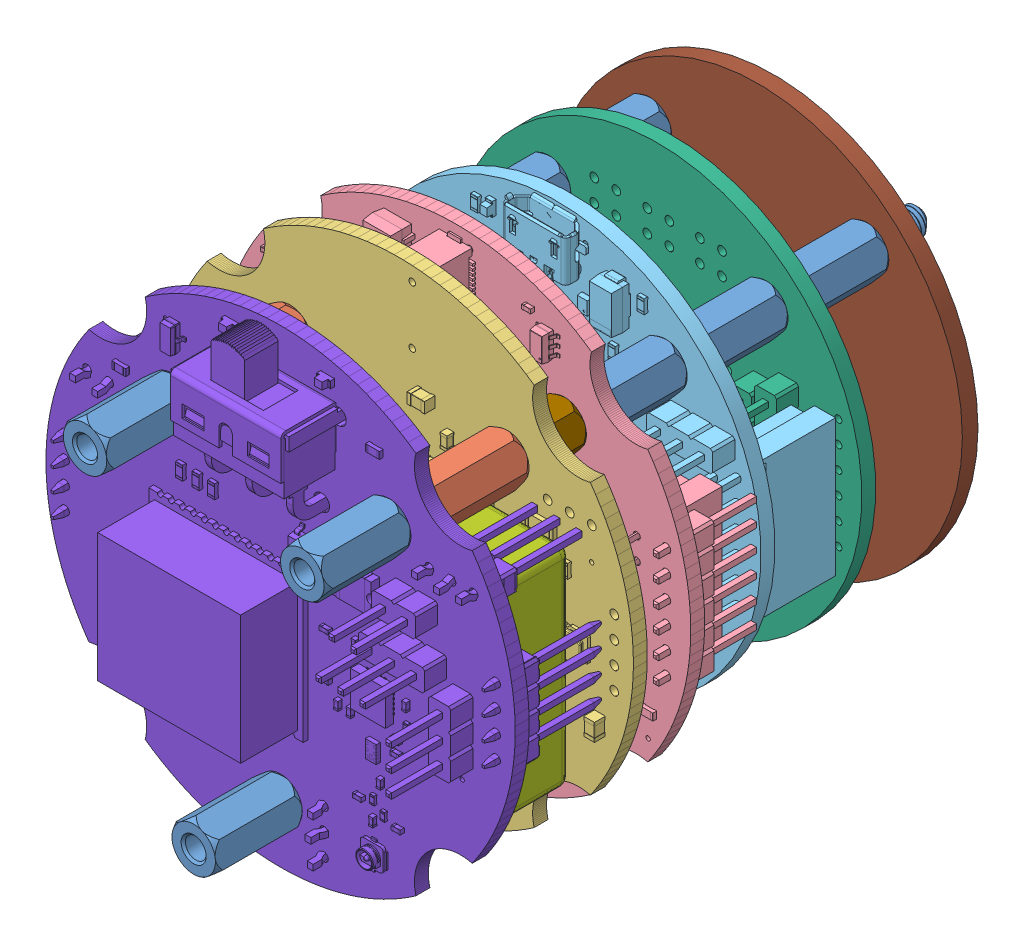
SolidWorks assembly asmPCBs, configuration Default. Lengths in mm.
Overall size (115.92 54.48 71.46).
30 component instances, 13 part files, 60 mates.
Components (placement in the parent):
- Hex Spacer MF M3 L10mm-25: Hex Spacer MF M3 L10mm [Default] at (-77.0093 15.9239 22.7752) x (0.987208 0.159439 0) z (0 0 -1) size (6.67 6.55 16.46)
- Hex Spacer MF M3 L10mm-24: Hex Spacer MF M3 L10mm [Default] at (-49.4701 6.9795 22.7752) x (0.923728 0.383049 0) z (0 0 -1) size (6.67 6.55 16.46)
- Hex Spacer MF M3 L12mm-26: Hex Spacer MF M3 L12mm [Default] at (31.272 -32.1614 9.1752) x (-0.938217 0.346047 0) z (0 0 -1) size (7.82 9.65 20.19)
- Hex Spacer MF M3 L12mm-27: Hex Spacer MF M3 L12mm [Default] at (-13.4807 82.2938 9.1752) x (0.015996 -0.999872 0) z (0 0 -1) size (7.82 9.65 20.19)
- Hex Spacer MF M3 L12mm-28: Hex Spacer MF M3 L12mm [Default] at (-10.1897 -31.112 9.1752) x (-0.455522 0.890225 0) z (0 0 -1) size (7.82 9.65 20.19)
- PCB_B-1: PCB_B [Default] at (-25.021 8.8014 7.5752) size (53.99 53.99 3.2)
- PCB_C-1: PCB_C [Default] at (-25.021 8.8014 0.9752) size (53.99 54.16 14.64)
- Hex Spacer MF M3 L10mm-26: Hex Spacer MF M3 L10mm [Default] at (-64.6583 -16.7727 22.7752) x (0.990934 0.134353 0) z (0 0 -1) size (6.67 6.55 16.46)
- PCB_D-1: PCB_D [Default] at (-25.021 8.8014 -10.6248) size (47 47 18.65)
- Hex Spacer MF M3 L10mm-28: Hex Spacer MF M3 L10mm [Default] at (-0.5719 37.6234 -9.0248) x (-0.923728 -0.383049 0) z (0 0 -1) size (6.67 6.55 16.46)
- Hex Spacer MF M3 L10mm-29: Hex Spacer MF M3 L10mm [Default] at (24.4281 37.6234 -9.0248) x (-0.923728 -0.383049 0) z (0 0 -1) size (6.67 6.55 16.46)
- Hex Spacer MF M3 L10mm-30: Hex Spacer MF M3 L10mm [Default] at (11.9281 3.9234 -9.0248) x (-0.923728 -0.383049 0) z (0 0 -1) size (6.67 6.55 16.46)
- Hex Spacer MF M3 L10mm-18: Hex Spacer MF M3 L10mm [Default] at (0.6106 34.3837 -20.6248) x (-0.95329 -0.302056 0) z (0 0 -1) size (6.67 6.55 16.46)
- Hex Spacer MF M3 L10mm-16: Hex Spacer MF M3 L10mm [Default] at (11.8127 4.1987 -20.6248) x (-0.920844 -0.389932 0) z (0 0 -1) size (6.67 6.55 16.46)
- Hex Spacer MF M3 L10mm-17: Hex Spacer MF M3 L10mm [Default] at (24.4281 37.6234 -20.6248) x (-0.923728 -0.383049 0) z (0 0 -1) size (6.67 6.55 16.46)
- PCB_E-1: PCB_E [Default] at (-25.021 8.8014 -22.2248) size (47 47 11.54)
- Bateria Li-Po-1: Bateria Li-Po [Default] at (-24.6522 6.5974 19.2752) x (1 0 0) z (0 1 0) size (42 8.5 24)
- PCB_A-3: PCB_A [Default] at (-25.021 8.8014 21.1752) size (53.99 54.31 20.71)
- Hex Spacer MF M3 L5mm-1: Hex Spacer MF M3 L5mm [Default] at (-34.2583 -15.229 2.5752) x (-0.923728 -0.383049 0) z (0 0 -1) size (7.82 9.65 13.19)
- Hex Spacer MF M3 L5mm-2: Hex Spacer MF M3 L5mm [Default] at (-21.7583 18.471 2.5752) x (-0.923728 -0.383049 0) z (0 0 -1) size (7.82 9.65 13.19)
- Hex Spacer MF M3 L5mm-3: Hex Spacer MF M3 L5mm [Default] at (-27.7771 24.5501 2.5752) x (0.97439 0.224864 0) z (0 0 -1) size (7.82 9.65 13.19)
- ESP32-WROOM-1: ESP32-WROOM [Default] at (-23.921 8.3714 2.5402) size (18.07 25.54 3.04)
- Hex Spacer MF M3 L10mm-31: Hex Spacer MF M3 L10mm [Default] at (14.9788 -11.5195 -32.2248) x (-0.999995 0.003024 0) z (0 0 -1) size (6.67 6.55 16.46)
- Hex Spacer MF M3 L10mm-32: Hex Spacer MF M3 L10mm [Default] at (24.4281 37.6234 -32.2248) x (-0.923728 -0.383049 0) z (0 0 -1) size (6.67 6.55 16.46)
- Hex Spacer MF M3 L10mm-33: Hex Spacer MF M3 L10mm [Default] at (-0.5719 37.6234 -32.2248) x (-0.923728 -0.383049 0) z (0 0 -1) size (6.67 6.55 16.46)
- Soporte-antena-1: Soporte-antena [Predeterminado] at (-25.0593 8.8938 -32.2248) x (-1 0 0) z (0 0 -1) size (47 47 1.8)
- Antena-1: Antena [Default] at (-20.5593 2.8938 -33.8248) x (-1 0 0) z (0 0 -1) size (19 14 2.55)
  - 0915AT43A0026E-1: 0915AT43A0026E [Default] at (2.7432 4.6736 1.65) size (8 2 0.9)
    - COMPOUND-1: COMPOUND [Default] at origin size (8 2 0.9)
  - COMPOUND_2-1: COMPOUND_2 [Default] at origin size (19 14 1.6)
Mates (geometry in assembly coordinates):
- Coincident40: coincident anti-aligned: plane of Hex Spacer MF M3 L10mm-24 through (-15.8533 23.6802 22.7752) normal (0 0 -1); plane of PCB_A-3 through (-4.9206 24.2485 22.7752) normal (0 0 1)
- Coincident42: coincident anti-aligned: plane of Hex Spacer MF M3 L10mm-26 through (-27.8905 -9.2143 22.7752) normal (0 0 -1); plane of PCB_A-3 through (-4.9206 24.2485 22.7752) normal (0 0 1)
- Coincident43: coincident anti-aligned: plane of Hex Spacer MF M3 L12mm-27 through (-10.0121 24.8919 9.1752) normal (0 0 -1); plane of PCB_B-1 through (-4.9206 24.2485 9.1752) normal (0 0 1)
- Concentric38: concentric aligned: cylinder of Hex Spacer MF M3 L10mm-24 through (-12.521 22.3014 26.5318) axis (0 0 1) radius 1.2; cylinder of PCB_A-3 through (-12.521 22.3014 20.3752) axis (0 0 1) radius 1.6
- Concentric39: concentric aligned: cylinder of Hex Spacer MF M3 L10mm-26 through (-25.021 -11.3986 26.5318) axis (0 0 1) radius 1.2; cylinder of PCB_A-3 through (-25.021 -11.3986 20.3752) axis (0 0 1) radius 1.6
- Concentric40: concentric aligned: cylinder of Hex Spacer MF M3 L10mm-24 through (-12.521 22.3014 26.5318) axis (0 0 1) radius 1.2; cylinder of Hex Spacer MF M3 L12mm-27 through (-12.521 22.3014 14.9318) axis (0 0 1) radius 1.2
- Concentric45: concentric aligned: cylinder of Hex Spacer MF M3 L10mm-25 through (-37.521 22.3014 26.5318) axis (0 0 1) radius 1.2; cylinder of PCB_A-3 through (-37.521 22.3014 20.3752) axis (0 0 1) radius 1.6
- Coincident49: coincident anti-aligned: plane of Hex Spacer MF M3 L10mm-25 through (-40.4449 24.4123 22.7752) normal (0 0 -1); plane of PCB_A-3 through (-4.9206 24.2485 22.7752) normal (0 0 1)
- Concentric46: concentric aligned: cylinder of Hex Spacer MF M3 L10mm-25 through (-37.521 22.3014 26.5318) axis (0 0 1) radius 1.2; cylinder of Hex Spacer MF M3 L12mm-28 through (-37.521 22.3014 14.9318) axis (0 0 1) radius 1.2
- Coincident50: coincident anti-aligned: plane of Hex Spacer MF M3 L12mm-28 through (-38.6295 18.8698 21.1752) normal (0 0 1); plane of PCB_A-3 through (-4.9206 24.2485 21.1752) normal (0 0 -1)
- Concentric47: concentric aligned: cylinder of Hex Spacer MF M3 L10mm-24 through (-12.521 22.3014 26.5318) axis (0 0 1) radius 1.2; cylinder of Hex Spacer MF M3 L12mm-27 through (-12.521 22.3014 14.9318) axis (0 0 1) radius 1.2
- Coincident51: coincident anti-aligned: plane of Hex Spacer MF M3 L12mm-27 through (-10.0121 24.8919 21.1752) normal (0 0 1); plane of PCB_A-3 through (-4.9206 24.2485 21.1752) normal (0 0 -1)
- Concentric49: concentric aligned: cylinder of Hex Spacer MF M3 L12mm-26 through (-25.021 -11.3986 14.9318) axis (0 0 1) radius 1.2; cylinder of Hex Spacer MF M3 L10mm-26 through (-25.021 -11.3986 26.5318) axis (0 0 1) radius 1.2
- Coincident52: coincident anti-aligned: plane of Hex Spacer MF M3 L12mm-26 through (-23.511 -14.6734 21.1752) normal (0 0 1); plane of PCB_A-3 through (-4.9206 24.2485 21.1752) normal (0 0 -1)
- Concentric50: concentric aligned: cylinder of Hex Spacer MF M3 L10mm-25 through (-37.521 22.3014 26.5318) axis (0 0 1) radius 1.2; cylinder of PCB_B-1 through (-37.521 22.3014 6.7752) axis (0 0 1) radius 1.6
- Concentric51: concentric aligned: cylinder of Hex Spacer MF M3 L10mm-24 through (-12.521 22.3014 26.5318) axis (0 0 1) radius 1.2; cylinder of PCB_B-1 through (-12.521 22.3014 6.7752) axis (0 0 1) radius 1.6
- Concentric52: concentric aligned: cylinder of Hex Spacer MF M3 L5mm-1 through (-25.021 -11.3986 5.3318) axis (0 0 1) radius 1.2; cylinder of PCB_C-1 through (-25.021 -11.3986 0.1752) axis (0 0 1) radius 1.6
- Concentric53: concentric aligned: cylinder of Hex Spacer MF M3 L5mm-2 through (-12.521 22.3014 5.3318) axis (0 0 1) radius 1.2; cylinder of PCB_C-1 through (-12.521 22.3014 0.1752) axis (0 0 1) radius 1.6
- Concentric54: concentric aligned: cylinder of Hex Spacer MF M3 L5mm-3 through (-37.521 22.3014 5.3318) axis (0 0 1) radius 1.2; cylinder of PCB_C-1 through (-37.521 22.3014 0.1752) axis (0 0 1) radius 1.6
- Coincident54: coincident anti-aligned: plane of PCB_C-1 through (-4.9206 24.2485 2.5752) normal (0 0 1); plane of Hex Spacer MF M3 L5mm-2 through (-9.1887 20.9227 2.5752) normal (0 0 -1)
- Coincident55: coincident anti-aligned: plane of PCB_C-1 through (-4.9206 24.2485 2.5752) normal (0 0 1); plane of Hex Spacer MF M3 L5mm-1 through (-21.6887 -12.7773 2.5752) normal (0 0 -1)
- Concentric55: concentric aligned: cylinder of Hex Spacer MF M3 L10mm-24 through (-12.521 22.3014 26.5318) axis (0 0 1) radius 1.2; cylinder of Hex Spacer MF M3 L5mm-2 through (-12.521 22.3014 5.3318) axis (0 0 1) radius 1.2
- Concentric56: concentric aligned: cylinder of Hex Spacer MF M3 L10mm-25 through (-37.521 22.3014 26.5318) axis (0 0 1) radius 1.2; cylinder of Hex Spacer MF M3 L5mm-3 through (-37.521 22.3014 5.3318) axis (0 0 1) radius 1.2
- Coincident56: coincident anti-aligned: plane of PCB_B-1 through (-4.9206 24.2485 7.5752) normal (0 0 -1); plane of Hex Spacer MF M3 L5mm-3 through (-40.5791 24.2127 7.5752) normal (0 0 1)
- Concentric57: concentric aligned: cylinder of Hex Spacer MF M3 L10mm-24 through (-12.521 22.3014 26.5318) axis (0 0 1) radius 1.2; cylinder of Hex Spacer MF M3 L10mm-29 through (-12.521 22.3014 -5.2682) axis (0 0 1) radius 1.2
- Concentric58: concentric aligned: cylinder of Hex Spacer MF M3 L10mm-25 through (-37.521 22.3014 26.5318) axis (0 0 1) radius 1.2; cylinder of Hex Spacer MF M3 L10mm-28 through (-37.521 22.3014 -5.2682) axis (0 0 1) radius 1.2
- Concentric59: concentric aligned: cylinder of Hex Spacer MF M3 L10mm-26 through (-25.021 -11.3986 26.5318) axis (0 0 1) radius 1.2; cylinder of Hex Spacer MF M3 L10mm-30 through (-25.021 -11.3986 -5.2682) axis (0 0 1) radius 1.2
- Coincident57: coincident anti-aligned: plane of PCB_C-1 through (-4.9206 24.2485 0.9752) normal (0 0 -1); plane of Hex Spacer MF M3 L10mm-28 through (-34.1887 20.9227 0.9752) normal (0 0 1)
- Coincident58: coincident anti-aligned: plane of PCB_C-1 through (-4.9206 24.2485 0.9752) normal (0 0 -1); plane of Hex Spacer MF M3 L10mm-29 through (-9.1887 20.9227 0.9752) normal (0 0 1)
- Coincident59: coincident anti-aligned: plane of PCB_C-1 through (-4.9206 24.2485 0.9752) normal (0 0 -1); plane of Hex Spacer MF M3 L10mm-30 through (-21.6887 -12.7773 0.9752) normal (0 0 1)
- Coincident60: coincident anti-aligned: plane of PCB_D-1 through (-1.521 8.8014 -9.0248) normal (0 0 1); plane of Hex Spacer MF M3 L10mm-28 through (-34.1887 20.9227 -9.0248) normal (0 0 -1)
- Concentric60: concentric aligned: cylinder of Hex Spacer MF M3 L10mm-25 through (-37.521 22.3014 26.5318) axis (0 0 1) radius 1.2; cylinder of PCB_D-1 through (-37.521 22.3014 -11.4248) axis (0 0 1) radius 1.6
- Concentric61: concentric aligned: cylinder of Hex Spacer MF M3 L10mm-24 through (-12.521 22.3014 26.5318) axis (0 0 1) radius 1.2; cylinder of PCB_D-1 through (-12.521 22.3014 -11.4248) axis (0 0 1) radius 1.6
- Concentric62: concentric aligned: cylinder of Hex Spacer MF M3 L10mm-25 through (-37.521 22.3014 26.5318) axis (0 0 1) radius 1.2; cylinder of Hex Spacer MF M3 L10mm-18 through (-37.521 22.3014 -16.8682) axis (0 0 1) radius 1.2
- Concentric63: concentric aligned: cylinder of Hex Spacer MF M3 L10mm-24 through (-12.521 22.3014 26.5318) axis (0 0 1) radius 1.2; cylinder of Hex Spacer MF M3 L10mm-17 through (-12.521 22.3014 -16.8682) axis (0 0 1) radius 1.2
- Concentric64: concentric aligned: cylinder of Hex Spacer MF M3 L10mm-26 through (-25.021 -11.3986 26.5318) axis (0 0 1) radius 1.2; cylinder of Hex Spacer MF M3 L10mm-16 through (-25.021 -11.3986 -16.8682) axis (0 0 1) radius 1.2
- Coincident61: coincident anti-aligned: plane of PCB_D-1 through (-1.521 8.8014 -10.6248) normal (0 0 -1); plane of Hex Spacer MF M3 L10mm-16 through (-21.6785 -12.7524 -10.6248) normal (0 0 1)
- Coincident62: coincident anti-aligned: plane of PCB_D-1 through (-1.521 8.8014 -10.6248) normal (0 0 -1); plane of Hex Spacer MF M3 L10mm-17 through (-9.1887 20.9227 -10.6248) normal (0 0 1)
- Coincident63: coincident anti-aligned: plane of PCB_D-1 through (-1.521 8.8014 -10.6248) normal (0 0 -1); plane of Hex Spacer MF M3 L10mm-18 through (-34.3199 20.6408 -10.6248) normal (0 0 1)
- Concentric65: concentric aligned: cylinder of Hex Spacer MF M3 L10mm-24 through (-12.521 22.3014 26.5318) axis (0 0 1) radius 1.2; cylinder of PCB_E-1 through (-12.521 22.3014 -23.0248) axis (0 0 1) radius 1.6
- Concentric66: concentric aligned: cylinder of Hex Spacer MF M3 L10mm-25 through (-37.521 22.3014 26.5318) axis (0 0 1) radius 1.2; cylinder of PCB_E-1 through (-37.521 22.3014 -23.0248) axis (0 0 1) radius 1.6
- Coincident64: coincident anti-aligned: plane of Hex Spacer MF M3 L10mm-17 through (-9.1887 20.9227 -20.6248) normal (0 0 -1); plane of PCB_E-1 through (-1.521 8.8014 -20.6248) normal (0 0 1)
- Coincident65: coincident anti-aligned: plane of PCB_B-1 through (-28.6873 7.4483 10.7752) normal (0 0 1); plane of Bateria Li-Po-1 through (-24.6522 6.5974 10.7752) normal (0 0 -1)
- Parallel5: parallel aligned: plane of Bateria Li-Po-1 through (-3.6522 -5.4026 10.7752) normal (1 0 0); plane of PCB_B-1 through (-19.0685 7.1464 9.2452) normal (1 0 0)
- Coincident67: coincident anti-aligned: plane of PCB_B-1 through (-4.9206 24.2485 7.5752) normal (0 0 -1); plane of Hex Spacer MF M3 L5mm-1 through (-21.6887 -12.7773 7.5752) normal (0 0 1)
- Coincident68: coincident anti-aligned: plane of PCB_C-1 through (-4.9206 24.2485 2.5752) normal (0 0 1); plane of ESP32-WROOM-1 through (-14.921 21.1214 2.5752) normal (0 0 -1)
- Distance1: distance = 5 mm aligned: plane of ESP32-WROOM-1 through (-31.921 20.1214 3.3752) normal (-1 0 0); plane of PCB_C-1 through (-26.921 34.4014 2.6252) normal (-1 0 0)
- Distance2: distance = 8 mm aligned: plane of ESP32-WROOM-1 through (-32.921 -4.3786 2.5752) normal (0 -1 0); plane of PCB_C-1 through (-17.221 -12.3786 2.6252) normal (0 -1 0)
- Concentric67: concentric aligned: cylinder of PCB_E-1 through (-25.021 -11.3986 -23.0248) axis (0 0 1) radius 1.6; cylinder of Hex Spacer MF M3 L10mm-31 through (-25.021 -11.3986 -28.4682) axis (0 0 1) radius 1.2
- Coincident69: coincident anti-aligned: plane of PCB_E-1 through (-1.521 8.8014 -22.2248) normal (0 0 -1); plane of Hex Spacer MF M3 L10mm-31 through (-22.4787 -13.9563 -22.2248) normal (0 0 1)
- Coincident72: coincident anti-aligned: plane of PCB_E-1 through (-1.521 8.8014 -22.2248) normal (0 0 -1); plane of Hex Spacer MF M3 L10mm-32 through (-9.1887 20.9227 -22.2248) normal (0 0 1)
- Concentric69: concentric aligned: cylinder of PCB_E-1 through (-12.521 22.3014 -23.0248) axis (0 0 1) radius 1.6; cylinder of Hex Spacer MF M3 L10mm-32 through (-12.521 22.3014 -28.4682) axis (0 0 1) radius 1.2
- Coincident73: coincident anti-aligned: plane of PCB_E-1 through (-1.521 8.8014 -22.2248) normal (0 0 -1); plane of Hex Spacer MF M3 L10mm-33 through (-34.1887 20.9227 -22.2248) normal (0 0 1)
- Concentric70: concentric aligned: cylinder of PCB_E-1 through (-37.521 22.3014 -23.0248) axis (0 0 1) radius 1.6; cylinder of Hex Spacer MF M3 L10mm-33 through (-37.521 22.3014 -28.4682) axis (0 0 1) radius 1.2
- Coincident74: coincident anti-aligned: plane of Hex Spacer MF M3 L10mm-33 through (-34.1887 20.9227 -32.2248) normal (0 0 -1); plane of Soporte-antena-1 through (-25.0593 8.8938 -32.2248) normal (0 0 1)
- Concentric71: concentric anti-aligned: cone of Hex Spacer MF M3 L10mm-33 through (-37.5593 22.3938 -36.2248) axis (0 0 -1); cylinder of Soporte-antena-1 through (-37.5593 22.3938 -34.0248) axis (0 0 1) radius 1.5
- Concentric72: concentric anti-aligned: cone of Hex Spacer MF M3 L10mm-32 through (-12.5593 22.3938 -36.2248) axis (0 0 -1); cylinder of Soporte-antena-1 through (-12.5593 22.3938 -34.0248) axis (0 0 1) radius 1.5
- Coincident75: coincident anti-aligned: plane of Soporte-antena-1 through (-25.0593 8.8938 -33.8248) normal (0 0 -1); plane of Antena-1/COMPOUND_2-1 through (-9.5593 -4.1062 -33.8248) normal (0 0 1)
- Coincident76: coincident anti-aligned: plane of Soporte-antena-1 through (-9.5593 -4.1062 -33.8248) normal (-1 0 0); plane of Antena-1/COMPOUND_2-1 through (-9.5593 9.8938 -33.8248) normal (1 0 0)
- Coincident77: coincident anti-aligned: plane of Soporte-antena-1 through (-9.5593 -4.1062 -33.8248) normal (0 1 0); plane of Antena-1/COMPOUND_2-1 through (-9.5593 -4.1062 -33.8248) normal (0 -1 0)
